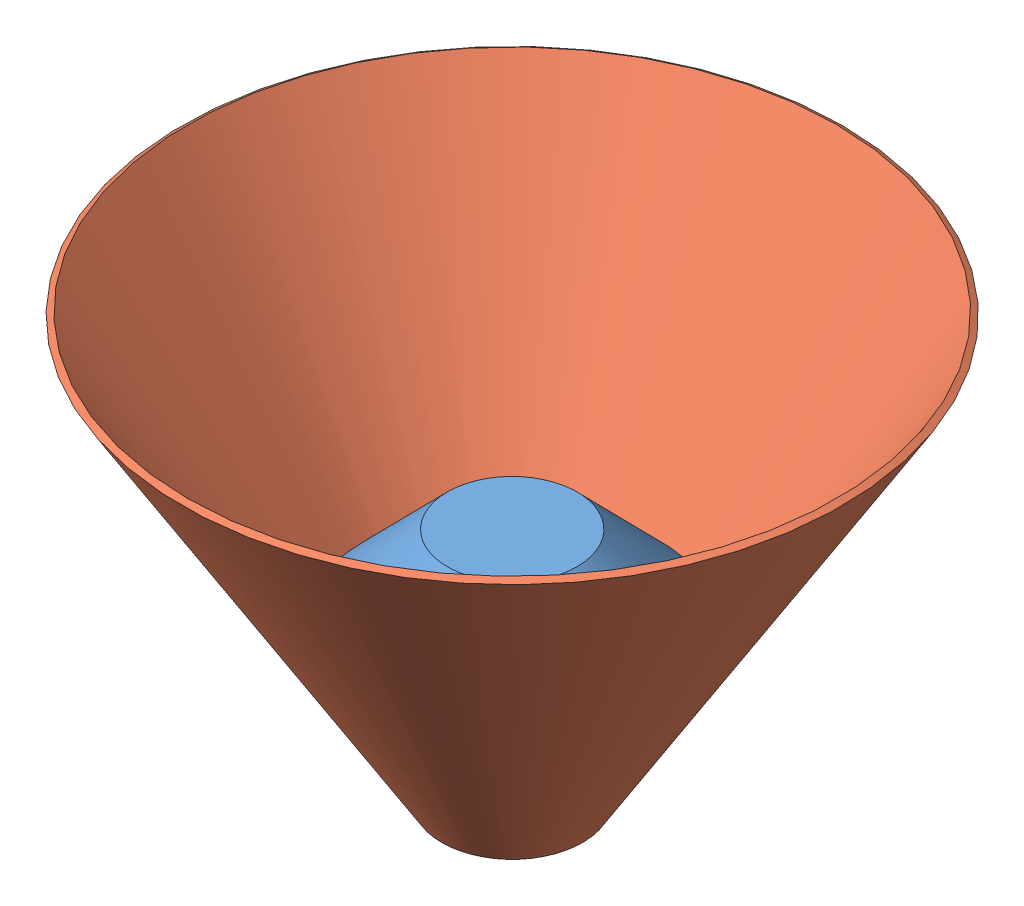
SolidWorks assembly Chamber_assembly, configuration Default. Lengths in mm.
Overall size (101.7 65.5 101.7).
2 component instances, 2 part files, 1 mates.
Components (placement in the parent):
- Chamber_inner-1: Chamber_inner [Default] at (82.9484 -5.4055 -2.5823) x (0.24578 0 0.969326) z (-0.969326 0 0.24578) size (45.64 33 45.64)
- Chamber_outer-1: Chamber_outer [Default] at (82.9484 -8.8738 -2.5823) size (101.7 65.5 101.7)
Mates (geometry in assembly coordinates):
- Coincident1: coincident anti-aligned: line of Chamber_inner-1 through (82.9484 14.0211 -2.5823) axis (0 1 0); line of Chamber_outer-1 through (82.9484 55.577 -2.5823) axis (0 -1 0)
